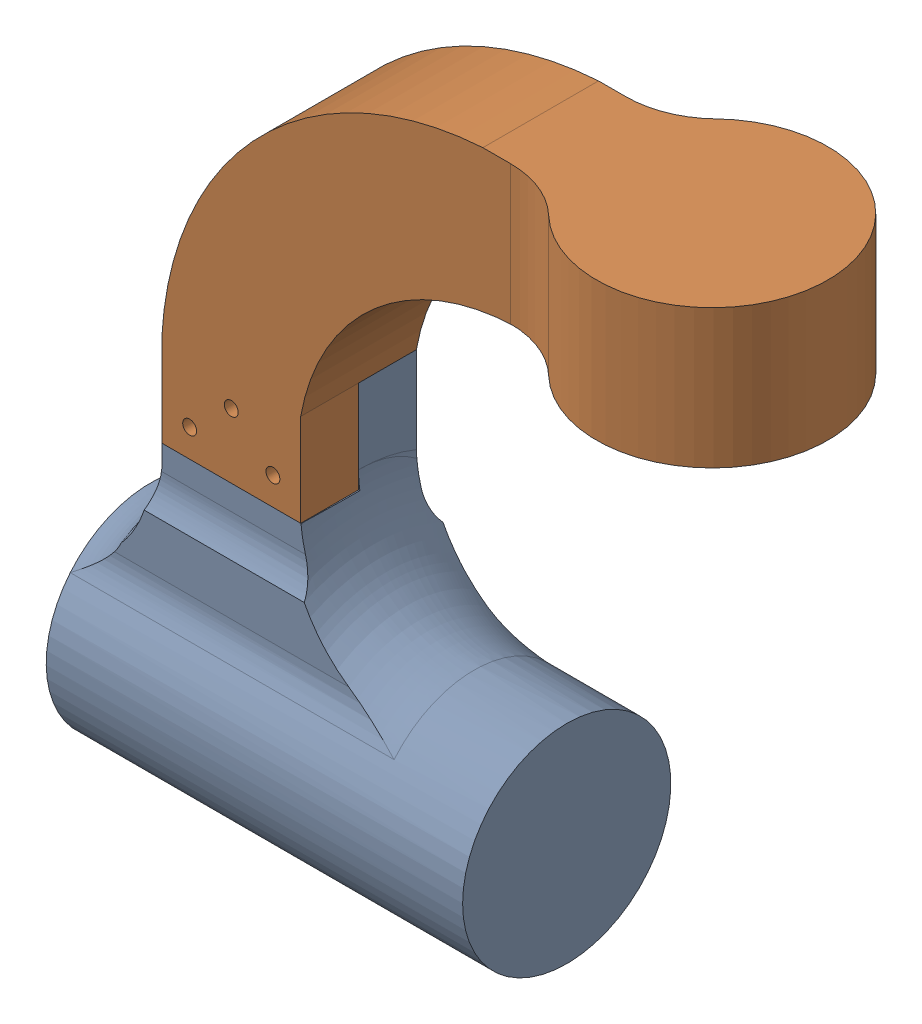
SolidWorks assembly MirrorWheel_Steer_Assembly, configuration Default. Lengths in mm.
Overall size (146.44 156.21 50).
2 component instances, 2 part files, 6 mates.
Components (placement in the parent):
- MirrorMotor_holder_end_wheels-1: MirrorMotor_holder_end_wheels [Default] at (-15 -43.7083 -12.5) x (0 1 0) z (-1 0 0) size (86.21 45 90)
- MirrorSteer_to_motor_holder-1: MirrorSteer_to_motor_holder [Default] at origin size (131.44 90 50)
Mates (geometry in assembly coordinates):
- Coincident1: coincident aligned: plane of MirrorSteer_to_motor_holder-1 through (0 0 0) normal (0 0 1)
- Coincident2: coincident aligned: plane of MirrorSteer_to_motor_holder-1 through (0 0 0) normal (0 1 0)
- Coincident3: coincident aligned: plane of MirrorSteer_to_motor_holder-1 through (0 0 0) normal (1 0 0)
- Coincident4: coincident anti-aligned: plane of MirrorMotor_holder_end_wheels-1 through (48 20 -12.5) normal (0 0 1); plane of MirrorSteer_to_motor_holder-1 through (49 0 -12.5) normal (0 0 -1)
- Coincident5: coincident anti-aligned: plane of MirrorMotor_holder_end_wheels-1 through (48 20 -25) normal (0 1 0); plane of MirrorSteer_to_motor_holder-1 through (49 20 -12.5) normal (0 -1 0)
- Coincident6: coincident aligned: plane of MirrorMotor_holder_end_wheels-1 through (30 -10 0) normal (1 0 0); plane of MirrorSteer_to_motor_holder-1 through (30 0 -25) normal (1 0 0)
